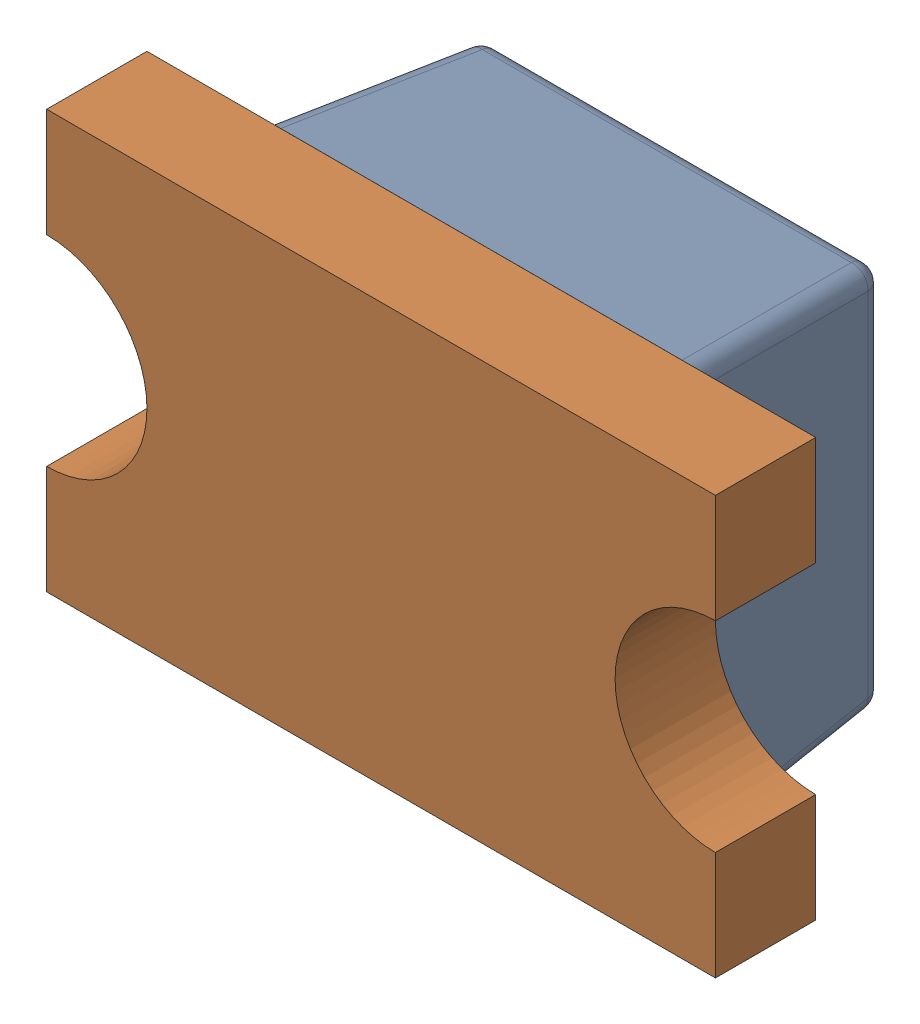
SolidWorks assembly D9, configuration Default. Lengths in mm.
Overall size (2 1.25 0.9).
2 component instances, 2 part files, 0 mates.
Components (placement in the parent):
- LED 0805 Lens RED-1: LED 0805 Lens RED [Default] at (49.9109 95.631 -1.2114) x (-1 0 0) z (0 -1 0) size (1.3 0.6 1.25)
- LED 0805 Base RED-1: LED 0805 Base RED [Default] at (49.9109 95.631 -1.2114) x (-1 0 0) z (0 -1 0) size (2 0.4 1.25)
